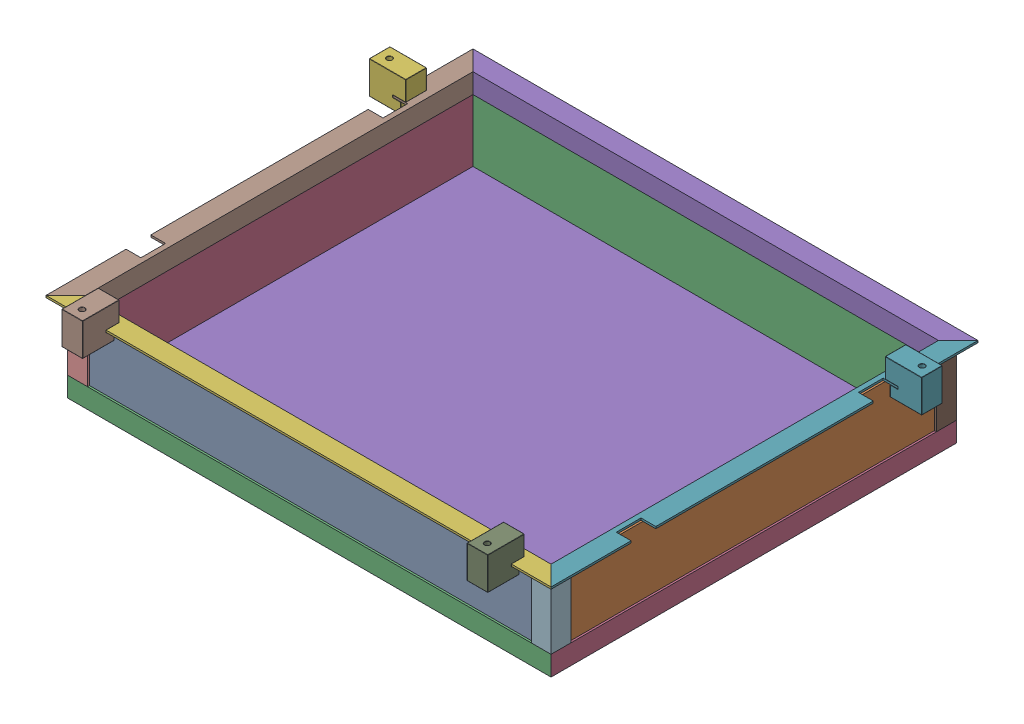
SolidWorks assembly W0003510-07-peripheral box, configuration Default. Lengths in mm.
Overall size (559 110 456).
21 component instances, 9 part files, 60 mates.
Components (placement in the parent):
- W0003510-68-460X88X3-1: W0003510-68-460X88X3 [Default] at (137.9161 187.8503 404.8916) size (475 86 5)
- W0003510-67-406X88X3-1: W0003510-67-406X88X3 [Default] at (380.4161 187.8503 206.8916) x (0 0 -1) z (0 1 0) size (406 5 86)
- W0003510-68-460X88X3-2: W0003510-68-460X88X3 [Default] at (137.9161 187.8503 3.8916) size (475 86 5)
- W0003510-67-406X88X3-2: W0003510-67-406X88X3 [Default] at (-104.5839 187.8503 206.8916) x (0 0 -1) z (0 -1 0) size (406 5 86)
- W0003510-70--L profile 460-1: W0003510-70--L profile 460 [Default] at (393.4161 232.8503 10.8916) x (0 0 -1) z (-1 0 0) size (20 20 511)
- W0003510-70--L profile 460-2: W0003510-70--L profile 460 [Default] at (-117.5839 232.8503 402.8916) x (0 0 1) z (1 0 0) size (20 20 511)
- W0003510-69--L profiel 400-1: W0003510-69--L profiel 400 [Default] at (373.4161 232.8503 422.8916) x (1 0 0) z (0 0 -1) size (20 20 432)
- W0003510-69--L profiel 400-2: W0003510-69--L profiel 400 [Default] at (-97.5839 232.8503 -9.1084) x (-1 0 0) z (0 0 1) size (20 20 432)
- W0003510-73--L profile 88-1: W0003510-73--L profile 88 [Default] at (-106.5839 162.8503 1.8916) x (0 0 1) z (0 1 0) size (20 20 68)
- W0003510-73--L profile 88-2: W0003510-73--L profile 88 [Default] at (-106.5839 162.8503 411.8916) x (1 0 0) z (0 1 0) size (20 20 68)
- W0003510-73--L profile 88-3: W0003510-73--L profile 88 [Default] at (382.4161 162.8503 1.8916) x (-1 0 0) z (0 1 0) size (20 20 68)
- W0003510-73--L profile 88-4: W0003510-73--L profile 88 [Default] at (382.4161 162.8503 411.8916) x (0 0 -1) z (0 1 0) size (20 20 68)
- W0003510-80---Lprofile 406-1: W0003510-80---Lprofile 406 [Default] at (-106.5839 142.8503 1.8916) size (20 20 410)
- W0003510-81--Lprofile 485-1: W0003510-81--Lprofile 485 [Default] at (382.4161 142.8503 1.8916) x (0 0 1) z (-1 0 0) size (20 20 489)
- W0003510-81--Lprofile 485-2: W0003510-81--Lprofile 485 [Default] at (-106.5839 142.8503 411.8916) x (0 0 -1) z (1 0 0) size (20 20 489)
- W0003510-80---Lprofile 406-2: W0003510-80---Lprofile 406 [Default] at (382.4161 142.8503 411.8916) x (-1 0 0) z (0 0 -1) size (20 20 410)
- W0003510-82-bottom plate-1: W0003510-82-bottom plate [Default] at (137.9161 147.8503 206.8916) x (1 0 0) z (0 -1 0) size (475 396 3)
- W0003510-83- suspension holder box-1: W0003510-83- suspension holder box [Default] at (-141.5839 252.8503 71.8916) x (1 0 0) z (0 0 -1) size (37 33 21)
- W0003510-83- suspension holder box-2: W0003510-83- suspension holder box [Default] at (417.4161 252.8503 50.8916) x (-1 0 0) z (0 0 1) size (37 33 21)
- W0003510-83- suspension holder box-3: W0003510-83- suspension holder box [Default] at (-56.5839 252.8503 446.8916) x (0 0 -1) z (-1 0 0) size (37 33 21)
- W0003510-83- suspension holder box-4: W0003510-83- suspension holder box [Default] at (353.4161 252.8503 446.8916) x (0 0 -1) z (-1 0 0) size (37 33 21)
Mates (geometry in assembly coordinates):
- Coincident1: coincident anti-aligned: plane of W0003510-68-460X88X3-1 through (375.4161 144.8503 409.8916) normal (1 0 0); plane of W0003510-67-406X88X3-1 through (375.4161 187.8503 206.8916) normal (-1 0 0)
- Coincident2: coincident aligned: plane of W0003510-68-460X88X3-1 through (-99.5839 230.8503 409.8916) normal (0 1 0); plane of W0003510-67-406X88X3-1 through (375.4161 230.8503 409.8916) normal (0 1 0)
- Coincident3: coincident aligned: plane of W0003510-68-460X88X3-1 through (137.9161 187.8503 409.8916) normal (0 0 1); plane of W0003510-67-406X88X3-1 through (375.4161 230.8503 409.8916) normal (0 0 1)
- Coincident4: coincident anti-aligned: plane of W0003510-67-406X88X3-1 through (375.4161 187.8503 206.8916) normal (-1 0 0); plane of W0003510-68-460X88X3-2 through (375.4161 144.8503 8.8916) normal (1 0 0)
- Coincident5: coincident aligned: plane of W0003510-67-406X88X3-1 through (375.4161 230.8503 3.8916) normal (0 0 -1); plane of W0003510-68-460X88X3-2 through (137.9161 187.8503 3.8916) normal (0 0 -1)
- Coincident6: coincident aligned: plane of W0003510-67-406X88X3-1 through (375.4161 230.8503 409.8916) normal (0 1 0); plane of W0003510-68-460X88X3-2 through (-99.5839 230.8503 8.8916) normal (0 1 0)
- Coincident7: coincident anti-aligned: plane of W0003510-68-460X88X3-2 through (-99.5839 144.8503 8.8916) normal (-1 0 0); plane of W0003510-67-406X88X3-2 through (-99.5839 187.8503 206.8916) normal (1 0 0)
- Coincident8: coincident aligned: plane of W0003510-68-460X88X3-2 through (-99.5839 230.8503 8.8916) normal (0 1 0); plane of W0003510-67-406X88X3-2 through (-99.5839 230.8503 409.8916) normal (0 1 0)
- Coincident9: coincident aligned: plane of W0003510-68-460X88X3-2 through (137.9161 187.8503 3.8916) normal (0 0 -1); plane of W0003510-67-406X88X3-2 through (-99.5839 144.8503 3.8916) normal (0 0 -1)
- Coincident10: coincident anti-aligned: plane of W0003510-68-460X88X3-2 through (137.9161 187.8503 8.8916) normal (0 0 1); plane of W0003510-70--L profiel 460-1 through (-117.5839 212.8503 8.8916) normal (0 0 -1)
- Coincident11: coincident anti-aligned: plane of W0003510-68-460X88X3-2 through (-99.5839 230.8503 8.8916) normal (0 1 0); plane of W0003510-70--L profiel 460-1 through (-117.5839 230.8503 8.8916) normal (0 -1 0)
- Coincident12: coincident: plane of W0003510-67-406X88X3-1 through (375.4161 187.8503 206.8916) normal (-1 0 0); line of W0003510-70--L profiel 460-1 through (375.4161 212.8503 8.8916) axis (0 1 0)
- Coincident13: coincident anti-aligned: plane of W0003510-68-460X88X3-1 through (137.9161 187.8503 404.8916) normal (0 0 -1); plane of W0003510-70--L profiel 460-2 through (393.4161 212.8503 404.8916) normal (0 0 1)
- Coincident14: coincident anti-aligned: plane of W0003510-68-460X88X3-1 through (-99.5839 230.8503 409.8916) normal (0 1 0); plane of W0003510-70--L profiel 460-2 through (393.4161 230.8503 404.8916) normal (0 -1 0)
- Coincident15: coincident anti-aligned: line of W0003510-68-460X88X3-1 through (375.4161 144.8503 404.8916) axis (0 1 0); line of W0003510-70--L profiel 460-2 through (375.4161 230.8503 404.8916) axis (0 -1 0)
- Coincident16: coincident anti-aligned: plane of W0003510-67-406X88X3-1 through (375.4161 187.8503 206.8916) normal (-1 0 0); plane of W0003510-69--L profiel 400-1 through (375.4161 212.8503 -9.1084) normal (1 0 0)
- Coincident17: coincident anti-aligned: plane of W0003510-67-406X88X3-1 through (375.4161 230.8503 409.8916) normal (0 1 0); plane of W0003510-69--L profiel 400-1 through (375.4161 230.8503 -9.1084) normal (0 -1 0)
- Coincident18: coincident anti-aligned: plane of W0003510-70--L profiel 460-1 through (393.4161 207.8503 -9.1084) normal (0.707107 0 0.707107); plane of W0003510-69--L profiel 400-1 through (393.4161 207.8503 -9.1084) normal (-0.707107 0 -0.707107)
- Coincident19: coincident anti-aligned: plane of W0003510-67-406X88X3-2 through (-99.5839 187.8503 206.8916) normal (1 0 0); plane of W0003510-69--L profiel 400-2 through (-99.5839 212.8503 422.8916) normal (-1 0 0)
- Coincident20: coincident anti-aligned: plane of W0003510-67-406X88X3-2 through (-99.5839 230.8503 409.8916) normal (0 1 0); plane of W0003510-69--L profiel 400-2 through (-99.5839 230.8503 422.8916) normal (0 -1 0)
- Coincident35: coincident aligned: plane of W0003510-73--L profiel 88-1 through (-106.5839 162.8503 1.8916) normal (0 -1 0); plane of W0003510-73--L profiel 88-4 through (382.4161 162.8503 411.8916) normal (0 -1 0)
- Coincident36: coincident aligned: plane of W0003510-73--L profiel 88-1 through (-106.5839 162.8503 1.8916) normal (0 -1 0); plane of W0003510-73--L profiel 88-3 through (382.4161 162.8503 1.8916) normal (0 -1 0)
- Coincident37: coincident aligned: plane of W0003510-73--L profiel 88-1 through (-106.5839 162.8503 1.8916) normal (0 -1 0); plane of W0003510-73--L profiel 88-2 through (-106.5839 162.8503 411.8916) normal (0 -1 0)
- Coincident39: coincident anti-aligned: plane of W0003510-67-406X88X3-2 through (-99.5839 144.8503 3.8916) normal (0 0 -1); plane of W0003510-73--L profiel 88-1 through (-86.5839 230.8503 3.8916) normal (0 0 1)
- Coincident41: coincident anti-aligned: plane of W0003510-67-406X88X3-2 through (-104.5839 187.8503 206.8916) normal (-1 0 0); plane of W0003510-73--L profiel 88-1 through (-104.5839 230.8503 3.8916) normal (1 0 0)
- Coincident44: coincident anti-aligned: plane of W0003510-67-406X88X3-2 through (-104.5839 187.8503 206.8916) normal (-1 0 0); plane of W0003510-73--L profiel 88-2 through (-104.5839 230.8503 391.8916) normal (1 0 0)
- Coincident45: coincident anti-aligned: plane of W0003510-68-460X88X3-1 through (137.9161 187.8503 409.8916) normal (0 0 1); plane of W0003510-73--L profiel 88-2 through (-104.5839 230.8503 409.8916) normal (0 0 -1)
- Coincident46: coincident anti-aligned: plane of W0003510-68-460X88X3-2 through (137.9161 187.8503 3.8916) normal (0 0 -1); plane of W0003510-73--L profiel 88-3 through (380.4161 230.8503 3.8916) normal (0 0 1)
- Coincident47: coincident anti-aligned: plane of W0003510-67-406X88X3-1 through (380.4161 187.8503 206.8916) normal (1 0 0); plane of W0003510-73--L profiel 88-3 through (380.4161 230.8503 21.8916) normal (-1 0 0)
- Coincident48: coincident anti-aligned: plane of W0003510-68-460X88X3-1 through (137.9161 187.8503 409.8916) normal (0 0 1); plane of W0003510-73--L profiel 88-4 through (362.4161 230.8503 409.8916) normal (0 0 -1)
- Coincident49: coincident anti-aligned: plane of W0003510-67-406X88X3-1 through (380.4161 187.8503 206.8916) normal (1 0 0); plane of W0003510-73--L profiel 88-4 through (380.4161 230.8503 409.8916) normal (-1 0 0)
- Coincident50: coincident: plane of W0003510-68-460X88X3-2 through (137.9161 187.8503 8.8916) normal (0 0 1); line of W0003510-69--L profiel 400-2 through (-99.5839 212.8503 8.8916) axis (0 1 0)
- Coincident51: coincident anti-aligned: plane of W0003510-69--L profiel 400-2 through (-99.5839 230.8503 422.8916) normal (0 -1 0); plane of W0003510-73--L profiel 88-2 through (-106.5839 230.8503 411.8916) normal (0 1 0)
- Coincident52: coincident anti-aligned: plane of W0003510-67-406X88X3-2 through (-104.5839 187.8503 206.8916) normal (-1 0 0); plane of W0003510-80---Lprofiel 406-1 through (-104.5839 144.8503 411.8916) normal (1 0 0)
- Coincident53: coincident anti-aligned: plane of W0003510-67-406X88X3-2 through (-99.5839 144.8503 409.8916) normal (0 -1 0); plane of W0003510-80---Lprofiel 406-1 through (-86.5839 144.8503 411.8916) normal (0 1 0)
- Coincident54: coincident aligned: line of W0003510-67-406X88X3-2 through (-104.5839 144.8503 3.8916) axis (0 1 0); line of W0003510-80---Lprofiel 406-1 through (-104.5839 144.8503 3.8916) axis (0 1 0)
- Coincident55: coincident anti-aligned: plane of W0003510-67-406X88X3-1 through (375.4161 144.8503 409.8916) normal (0 -1 0); plane of W0003510-81--Lprofiel 485-1 through (-106.5839 144.8503 21.8916) normal (0 1 0)
- Coincident58: coincident anti-aligned: plane of W0003510-68-460X88X3-2 through (137.9161 187.8503 3.8916) normal (0 0 -1); plane of W0003510-81--Lprofiel 485-1 through (-106.5839 144.8503 3.8916) normal (0 0 1)
- Coincident59: coincident anti-aligned: line of W0003510-67-406X88X3-1 through (380.4161 230.8503 3.8916) axis (0 -1 0); line of W0003510-81--Lprofiel 485-1 through (380.4161 144.8503 3.8916) axis (0 1 0)
- Coincident60: coincident anti-aligned: plane of W0003510-68-460X88X3-1 through (137.9161 187.8503 409.8916) normal (0 0 1); plane of W0003510-81--Lprofiel 485-2 through (382.4161 144.8503 409.8916) normal (0 0 -1)
- Coincident61: coincident aligned: plane of W0003510-80---Lprofiel 406-1 through (-106.5839 142.8503 411.8916) normal (0 -1 0); plane of W0003510-81--Lprofiel 485-2 through (382.4161 142.8503 411.8916) normal (0 -1 0)
- Coincident62: coincident aligned: line of W0003510-67-406X88X3-1 through (380.4161 144.8503 409.8916) axis (0 1 0); line of W0003510-81--Lprofiel 485-2 through (380.4161 144.8503 409.8916) axis (0 1 0)
- Coincident63: coincident anti-aligned: plane of W0003510-67-406X88X3-1 through (380.4161 187.8503 206.8916) normal (1 0 0); plane of W0003510-80---Lprofiel 406-2 through (380.4161 144.8503 1.8916) normal (-1 0 0)
- Coincident64: coincident aligned: plane of W0003510-81--Lprofiel 485-2 through (382.4161 142.8503 411.8916) normal (0 -1 0); plane of W0003510-80---Lprofiel 406-2 through (382.4161 142.8503 1.8916) normal (0 -1 0)
- Coincident65: coincident aligned: line of W0003510-81--Lprofiel 485-1 through (382.4161 162.8503 1.8916) axis (0 -1 0); line of W0003510-80---Lprofiel 406-2 through (382.4161 162.8503 1.8916) axis (0 -1 0)
- Coincident66: coincident anti-aligned: plane of W0003510-68-460X88X3-1 through (137.9161 187.8503 404.8916) normal (0 0 -1); plane of W0003510-82-onderplaat-1 through (-99.5839 144.8503 404.8916) normal (0 0 1)
- Coincident67: coincident anti-aligned: plane of W0003510-67-406X88X3-2 through (-99.5839 187.8503 206.8916) normal (1 0 0); plane of W0003510-82-onderplaat-1 through (-99.5839 144.8503 8.8916) normal (-1 0 0)
- Coincident68: coincident: line of W0003510-80---Lprofiel 406-2 through (362.4161 144.8503 21.8916) axis (0 0 1); plane of W0003510-82-onderplaat-1 through (137.9161 144.8503 206.8916) normal (0 -1 0)
- Coincident69: coincident aligned: plane of W0003510-83- ophaning onderbak-1 through (-141.5839 219.8503 50.8916) normal (0 -1 0); plane of W0003510-83- ophaning onderbak-2 through (417.4161 219.8503 71.8916) normal (0 -1 0)
- Coincident70: coincident aligned: plane of W0003510-83- ophaning onderbak-1 through (-141.5839 219.8503 50.8916) normal (0 -1 0); plane of W0003510-83- ophaning onderbak-3 through (-77.5839 219.8503 446.8916) normal (0 -1 0)
- Coincident71: coincident aligned: plane of W0003510-83- ophaning onderbak-1 through (-141.5839 219.8503 50.8916) normal (0 -1 0); plane of W0003510-83- ophaning onderbak-4 through (332.4161 219.8503 446.8916) normal (0 -1 0)
- Coincident74: coincident anti-aligned: plane of W0003510-69--L profiel 400-1 through (373.4161 232.8503 -9.1084) normal (0 1 0); plane of W0003510-83- ophaning onderbak-4 through (332.4161 232.8503 422.8916) normal (0 -1 0)
- Coincident75: coincident anti-aligned: plane of W0003510-69--L profiel 400-1 through (393.4161 230.8503 -9.1084) normal (1 0 0); plane of W0003510-83- ophaning onderbak-2 through (393.4161 230.6503 71.8916) normal (-1 0 0)
- Distance2: distance = 60 mm aligned: plane of W0003510-70--L profiel 460-1 through (-117.5839 230.8503 -9.1084) normal (0 0 -1); plane of W0003510-83- ophaning onderbak-2 through (417.4161 252.8503 50.8916) normal (0 0 -1)
- Coincident79: coincident anti-aligned: plane of W0003510-70--L profiel 460-2 through (393.4161 230.8503 422.8916) normal (0 0 1); plane of W0003510-83- ophaning onderbak-4 through (332.4161 230.6503 422.8916) normal (0 0 -1)
- Distance3: distance = 40 mm aligned: plane of W0003510-69--L profiel 400-1 through (393.4161 230.8503 -9.1084) normal (1 0 0); plane of W0003510-83- ophaning onderbak-4 through (353.4161 252.8503 446.8916) normal (1 0 0)
- Coincident81: coincident anti-aligned: plane of W0003510-70--L profiel 460-2 through (393.4161 230.8503 422.8916) normal (0 0 1); plane of W0003510-83- ophaning onderbak-3 through (-77.5839 230.6503 422.8916) normal (0 0 -1)
- Distance4: distance = 40 mm aligned: plane of W0003510-69--L profiel 400-2 through (-117.5839 230.8503 422.8916) normal (-1 0 0); plane of W0003510-83- ophaning onderbak-3 through (-77.5839 252.8503 446.8916) normal (-1 0 0)
- Coincident83: coincident anti-aligned: plane of W0003510-69--L profiel 400-2 through (-117.5839 230.8503 422.8916) normal (-1 0 0); plane of W0003510-83- ophaning onderbak-1 through (-117.5839 230.6503 50.8916) normal (1 0 0)
- Coincident84: coincident aligned: plane of W0003510-83- ophaning onderbak-1 through (-141.5839 252.8503 71.8916) normal (0 0 1); plane of W0003510-83- ophaning onderbak-2 through (417.4161 252.8503 71.8916) normal (0 0 1)
